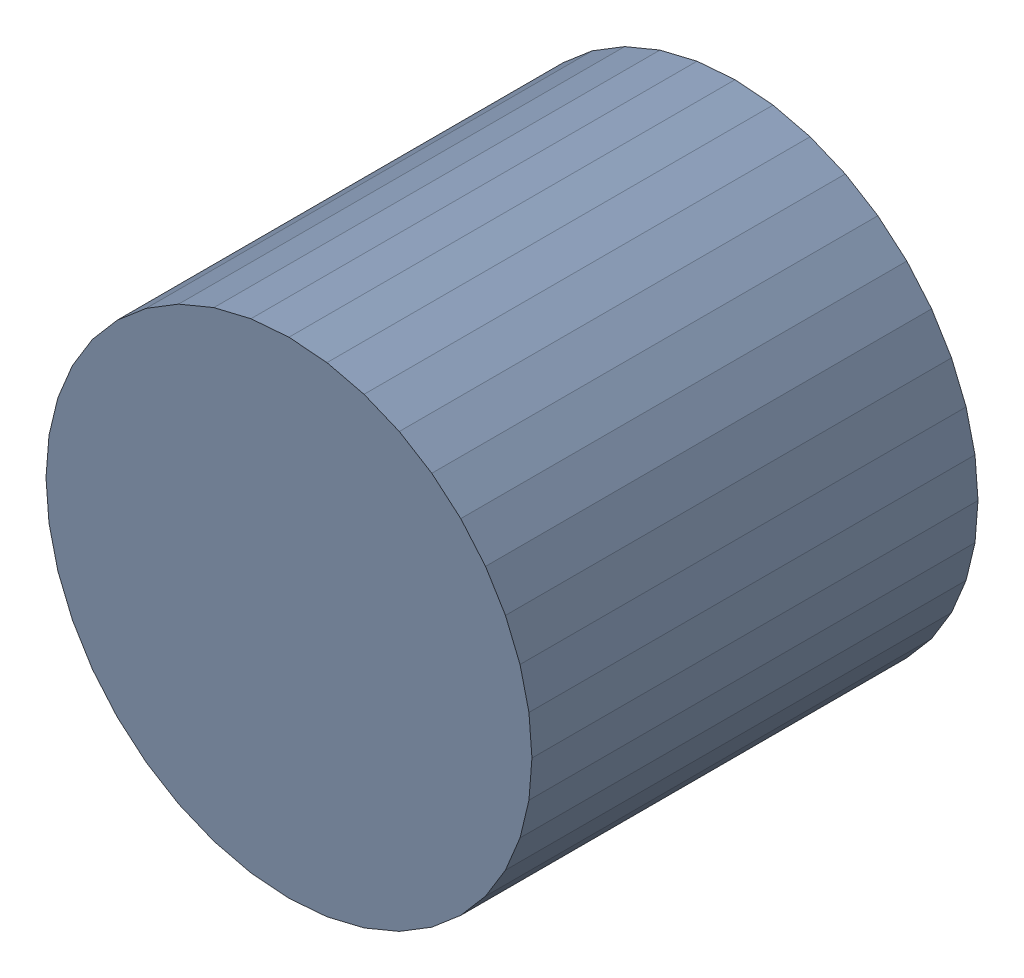
SolidWorks assembly USB45_C5, configuration Default. Lengths in mm.
Overall size (6.32 6.32 5.8).
2 component instances, 1 part files, 0 mates.
Components (placement in the parent):
- 384312384-1: 384312384 [Default] at (149.86 34.163 -6.9024) size (6.32 6.32 5.8)
  - Extruded_7-1: Extruded_7 [Default] at origin size (6.32 6.32 5.8)
